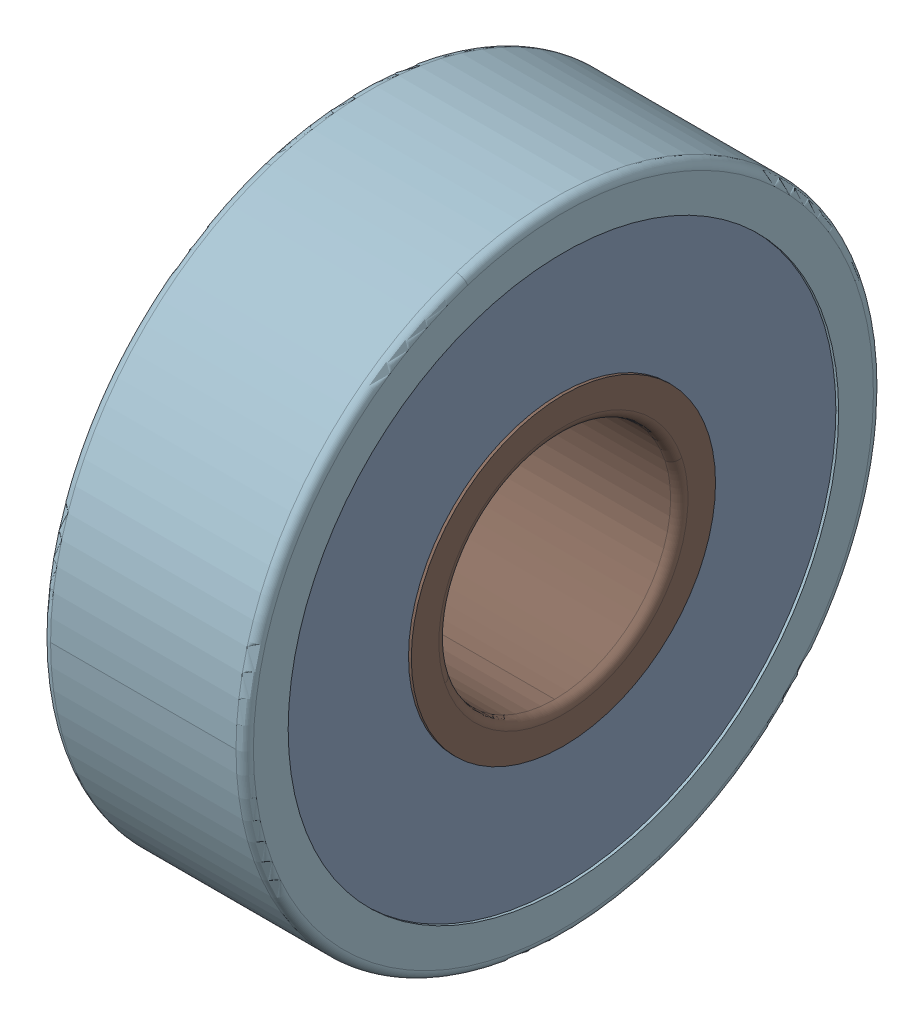
SolidWorks assembly 608VV, configuration Default. Lengths in mm.
Overall size (7 22 22).
12 component instances, 5 part files, 0 mates.
Components (placement in the parent):
- 608VV_3-1: 608VV_3 [Default] at origin size (0.29 19 19)
- 608VV_5-1: 608VV_5 [Default] at (3.5 5.3033 5.3033) x (1 0 0) z (0 -1 0) size (4.2 4.2 4.2)
- 608VV_5-2: 608VV_5 [Default] at (3.5 7.5 0) x (1 0 0) z (0 -1 0) size (4.2 4.2 4.2)
- 608VV_5-3: 608VV_5 [Default] at (3.5 5.3033 -5.3033) x (1 0 0) z (0 -1 0) size (4.2 4.2 4.2)
- 608VV_5-4: 608VV_5 [Default] at (3.5 0 -7.5) x (1 0 0) z (0 -1 0) size (4.2 4.2 4.2)
- 608VV_5-5: 608VV_5 [Default] at (3.5 -5.3033 -5.3033) x (1 0 0) z (0 -1 0) size (4.2 4.2 4.2)
- 608VV_5-6: 608VV_5 [Default] at (3.5 -7.5 0) x (1 0 0) z (0 -1 0) size (4.2 4.2 4.2)
- 608VV_5-7: 608VV_5 [Default] at (3.5 -5.3033 5.3033) x (1 0 0) z (0 -1 0) size (4.2 4.2 4.2)
- 608VV_5-8: 608VV_5 [Default] at (3.5 0 7.5) x (1 0 0) z (0 -1 0) size (4.2 4.2 4.2)
- 608VV_14-1: 608VV_14 [Default] at (0.77 0 0) x (-1 0 0) z (0 -1 0) size (0.29 19 19)
- 608VV_16-1: 608VV_16 [Default] x (1 0 0) z (0 -1 0) size (7 12.14 12.14)
- 608VV_18-1: 608VV_18 [Default] at origin size (7 22 22)
